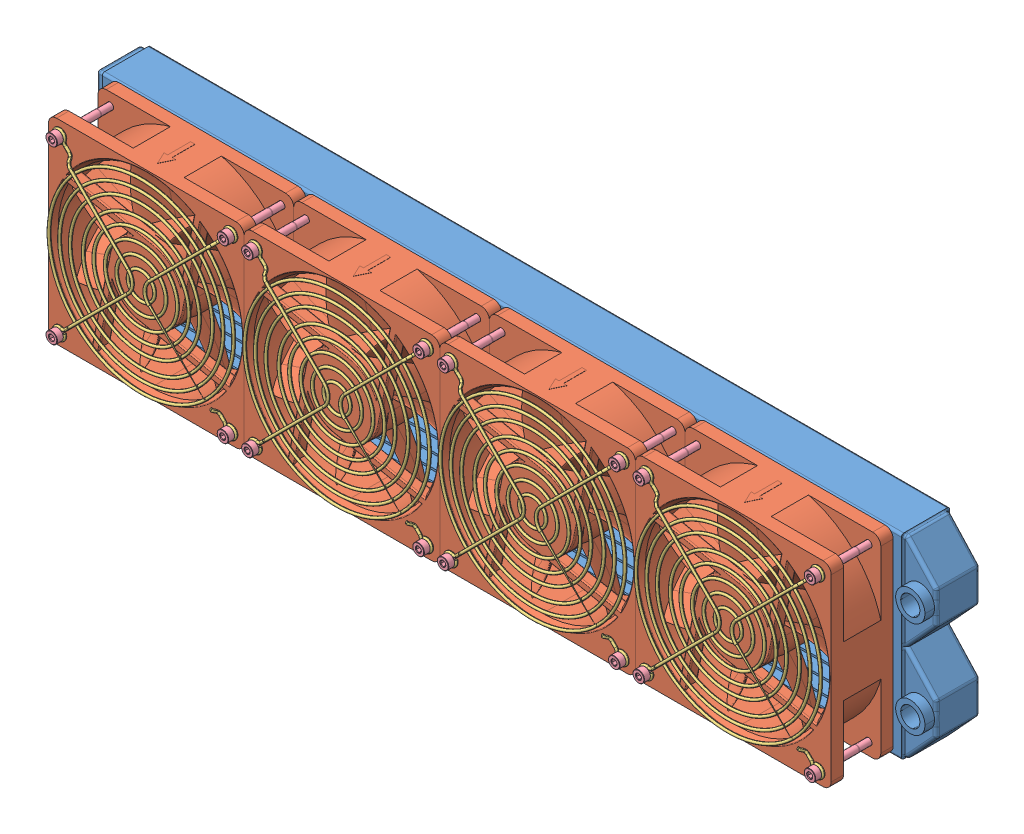
SolidWorks assembly EN-A0201-AA-4x Koolance Radiator Assembly, configuration Default. Lengths in mm.
Overall size (573.51 213.64 79.1).
25 component instances, 4 part files, 60 mates.
Components (placement in the parent):
- EN-00045-AA-CU1320V-1: EN-00045-AA-CU1320V [Default] at (-252.5 -60 -14.8) size (515 120 34.1)
- EN-00046-12038HBK-184 (Fan)-1: EN-00046-12038HBK-184 (Fan) [Default] at (121.332 -8.1772 33.6) x (-1 0 0) z (0 0 -1) size (120.02 137.53 39.89)
- EN-00046-12038HBK-184 (Fan)-2: EN-00046-12038HBK-184 (Fan) [Default] at (1.332 -8.1772 33.6) x (-1 0 0) z (0 0 -1) size (120.02 137.53 39.89)
- EN-00046-12038HBK-184 (Fan)-3: EN-00046-12038HBK-184 (Fan) [Default] at (-118.668 -8.1772 33.6) x (-1 0 0) z (0 0 -1) size (120.02 137.53 39.89)
- EN-00046-12038HBK-184 (Fan)-4: EN-00046-12038HBK-184 (Fan) [Default] at (-238.668 -8.1772 33.6) x (-1 0 0) z (0 0 -1) size (120.02 137.53 39.89)
- EN-00078-AA-GRL-AP002P (Grill)-1: EN-00078-AA-GRL-AP002P (Grill) [Default] at (172.4974 0.0026 55.8) x (-0.707107 -0.707107 0) z (-0.707107 0.707107 0) size (156.8 13.6 156.8)
- EN-00078-AA-GRL-AP002P (Grill)-3: EN-00078-AA-GRL-AP002P (Grill) [Default] at (52.4974 0.0026 55.8) x (-0.707107 -0.707107 0) z (-0.707107 0.707107 0) size (156.8 13.6 156.8)
- EN-00078-AA-GRL-AP002P (Grill)-4: EN-00078-AA-GRL-AP002P (Grill) [Default] at (-67.5026 0.0026 55.8) x (-0.707107 -0.707107 0) z (-0.707107 0.707107 0) size (156.8 13.6 156.8)
- EN-00078-AA-GRL-AP002P (Grill)-5: EN-00078-AA-GRL-AP002P (Grill) [Default] at (-187.5026 0.0026 55.8) x (-0.707107 -0.707107 0) z (-0.707107 0.707107 0) size (156.8 13.6 156.8)
- FS-BLACK-OXIDE C12.9 SHCS, M4x0.7-45 (91290A145)-17: FS-BLACK-OXIDE C12.9 SHCS, M4x0.7-45 (91290A145) [91290A145] at (-240.0052 52.5052 34) x (0.985048 0.172278 0) z (0 0 1) size (7 7 49.04)
- FS-BLACK-OXIDE C12.9 SHCS, M4x0.7-45 (91290A145)-18: FS-BLACK-OXIDE C12.9 SHCS, M4x0.7-45 (91290A145) [91290A145] at (-240.0052 -52.5 34) x (0.940441 0.339956 0) z (0 0 1) size (7 7 49.04)
- FS-BLACK-OXIDE C12.9 SHCS, M4x0.7-45 (91290A145)-19: FS-BLACK-OXIDE C12.9 SHCS, M4x0.7-45 (91290A145) [91290A145] at (-135 52.5052 34) size (7 7 49.04)
- FS-BLACK-OXIDE C12.9 SHCS, M4x0.7-45 (91290A145)-20: FS-BLACK-OXIDE C12.9 SHCS, M4x0.7-45 (91290A145) [91290A145] at (-135 -52.5 34) size (7 7 49.04)
- FS-BLACK-OXIDE C12.9 SHCS, M4x0.7-45 (91290A145)-21: FS-BLACK-OXIDE C12.9 SHCS, M4x0.7-45 (91290A145) [91290A145] at (-120.0052 -52.5 34) size (7 7 49.04)
- FS-BLACK-OXIDE C12.9 SHCS, M4x0.7-45 (91290A145)-22: FS-BLACK-OXIDE C12.9 SHCS, M4x0.7-45 (91290A145) [91290A145] at (-15 -52.5 34) size (7 7 49.04)
- FS-BLACK-OXIDE C12.9 SHCS, M4x0.7-45 (91290A145)-23: FS-BLACK-OXIDE C12.9 SHCS, M4x0.7-45 (91290A145) [91290A145] at (-15 52.5052 34) size (7 7 49.04)
- FS-BLACK-OXIDE C12.9 SHCS, M4x0.7-45 (91290A145)-24: FS-BLACK-OXIDE C12.9 SHCS, M4x0.7-45 (91290A145) [91290A145] at (-120.0052 52.5052 34) size (7 7 49.04)
- FS-BLACK-OXIDE C12.9 SHCS, M4x0.7-45 (91290A145)-25: FS-BLACK-OXIDE C12.9 SHCS, M4x0.7-45 (91290A145) [91290A145] at (-0.0052 52.5052 34) size (7 7 49.04)
- FS-BLACK-OXIDE C12.9 SHCS, M4x0.7-45 (91290A145)-26: FS-BLACK-OXIDE C12.9 SHCS, M4x0.7-45 (91290A145) [91290A145] at (105 52.5052 34) size (7 7 49.04)
- FS-BLACK-OXIDE C12.9 SHCS, M4x0.7-45 (91290A145)-27: FS-BLACK-OXIDE C12.9 SHCS, M4x0.7-45 (91290A145) [91290A145] at (105 -52.5 34) size (7 7 49.04)
- FS-BLACK-OXIDE C12.9 SHCS, M4x0.7-45 (91290A145)-28: FS-BLACK-OXIDE C12.9 SHCS, M4x0.7-45 (91290A145) [91290A145] at (-0.0052 -52.5 34) size (7 7 49.04)
- FS-BLACK-OXIDE C12.9 SHCS, M4x0.7-45 (91290A145)-29: FS-BLACK-OXIDE C12.9 SHCS, M4x0.7-45 (91290A145) [91290A145] at (119.9948 -52.5 34) size (7 7 49.04)
- FS-BLACK-OXIDE C12.9 SHCS, M4x0.7-45 (91290A145)-30: FS-BLACK-OXIDE C12.9 SHCS, M4x0.7-45 (91290A145) [91290A145] at (119.9948 52.5052 34) size (7 7 49.04)
- FS-BLACK-OXIDE C12.9 SHCS, M4x0.7-45 (91290A145)-31: FS-BLACK-OXIDE C12.9 SHCS, M4x0.7-45 (91290A145) [91290A145] at (225 52.5052 34) size (7 7 49.04)
- FS-BLACK-OXIDE C12.9 SHCS, M4x0.7-45 (91290A145)-32: FS-BLACK-OXIDE C12.9 SHCS, M4x0.7-45 (91290A145) [91290A145] at (225 -52.5 34) size (7 7 49.04)
Mates (geometry in assembly coordinates):
- Coincident1: coincident anti-aligned: plane of EN-00045-AA-CU1320V-1 through (-252.5 -60 14.8) normal (0 0 1); plane of EN-00046-12038HBK-184 (Fan)-1 through (232.5004 -60.0004 14.8) normal (0 0 -1)
- Concentric1: concentric anti-aligned: cylinder of EN-00045-AA-CU1320V-1 through (225 -52.5 14.8) axis (0 0 1) radius 1.65; cylinder of EN-00046-12038HBK-184 (Fan)-1 through (225 -52.5 52.8) axis (0 0 -1) radius 2.1001
- Parallel1: parallel aligned: plane of EN-00045-AA-CU1320V-1 through (-252.5 -60 14.8) normal (0 -1 0); plane of EN-00046-12038HBK-184 (Fan)-1 through (232.5004 -60.0004 14.8) normal (0 -1 0)
- Coincident3: coincident anti-aligned: plane of EN-00045-AA-CU1320V-1 through (-252.5 -60 14.8) normal (0 0 1); plane of EN-00046-12038HBK-184 (Fan)-2 through (112.5004 -60.0004 14.8) normal (0 0 -1)
- Concentric2: concentric anti-aligned: cylinder of EN-00045-AA-CU1320V-1 through (105 -52.5 14.8) axis (0 0 1) radius 1.65; cylinder of EN-00046-12038HBK-184 (Fan)-2 through (105 -52.5 52.8) axis (0 0 -1) radius 2.1001
- Parallel2: parallel aligned: plane of EN-00045-AA-CU1320V-1 through (-252.5 -60 14.8) normal (0 -1 0); plane of EN-00046-12038HBK-184 (Fan)-2 through (112.5004 -60.0004 14.8) normal (0 -1 0)
- Coincident5: coincident anti-aligned: plane of EN-00045-AA-CU1320V-1 through (-252.5 -60 14.8) normal (0 0 1); plane of EN-00046-12038HBK-184 (Fan)-3 through (-7.4996 -60.0004 14.8) normal (0 0 -1)
- Concentric3: concentric anti-aligned: cylinder of EN-00045-AA-CU1320V-1 through (-15 -52.5 14.8) axis (0 0 1) radius 1.65; cylinder of EN-00046-12038HBK-184 (Fan)-3 through (-15 -52.5 52.8) axis (0 0 -1) radius 2.1001
- Parallel3: parallel aligned: plane of EN-00045-AA-CU1320V-1 through (-252.5 -60 14.8) normal (0 -1 0); plane of EN-00046-12038HBK-184 (Fan)-3 through (-7.4996 -60.0004 14.8) normal (0 -1 0)
- Coincident7: coincident anti-aligned: plane of EN-00045-AA-CU1320V-1 through (-252.5 -60 14.8) normal (0 0 1); plane of EN-00046-12038HBK-184 (Fan)-4 through (-127.4996 -60.0004 14.8) normal (0 0 -1)
- Concentric4: concentric anti-aligned: cylinder of EN-00045-AA-CU1320V-1 through (-135 -52.5 14.8) axis (0 0 1) radius 1.65; cylinder of EN-00046-12038HBK-184 (Fan)-4 through (-135 -52.5 52.8) axis (0 0 -1) radius 2.1001
- Parallel4: parallel aligned: plane of EN-00045-AA-CU1320V-1 through (-252.5 -60 14.8) normal (0 -1 0); plane of EN-00046-12038HBK-184 (Fan)-4 through (-127.4996 -60.0004 14.8) normal (0 -1 0)
- Distance1: distance = 60 mm: plane of assembly through (0 0 0) normal (0 1 0); plane of assembly; plane of EN-00045-AA-CU1320V-1 through (-252.5 -60 14.8) normal (0 -1 0)
- Distance2: distance = 257.5 mm: plane of assembly through (0 0 0) normal (1 0 0); plane of assembly; plane of EN-00045-AA-CU1320V-1 through (-257.5 -60 -14.8) normal (-1 0 0)
- Distance3: distance = 14.8 mm: plane of assembly through (0 0 0) normal (0 0 1); plane of assembly; plane of EN-00045-AA-CU1320V-1 through (-252.5 -60 -14.8) normal (0 0 -1)
- Coincident8: coincident aligned: plane of EN-00046-12038HBK-184 (Fan)-1 through (232.5004 -60.0004 52.8) normal (0 0 1); plane of EN-00078-AA-GRL-AP002P (Grill)-1 through (172.4974 0.0026 52.8) normal (0 0 1)
- Concentric5: concentric aligned: cylinder of EN-00046-12038HBK-184 (Fan)-1 through (172.4974 0.0026 47.6487) axis (0 0 -1) radius 23.2442; circle of EN-00078-AA-GRL-AP002P (Grill)-1
- Distance4: distance = 0.0504 mm: point of EN-00078-AA-GRL-AP002P (Grill)-1
- Coincident13: coincident aligned: plane of EN-00046-12038HBK-184 (Fan)-2 through (112.5004 -60.0004 52.8) normal (0 0 1); plane of EN-00078-AA-GRL-AP002P (Grill)-2 through (14655.4509 -24504.2017 52.8) normal (0 0 1)
- Coincident14: coincident aligned: plane of EN-00046-12038HBK-184 (Fan)-2 through (112.5004 -60.0004 52.8) normal (0 0 1); plane of EN-00078-AA-GRL-AP002P (Grill)-3 through (52.4974 0.0026 52.8) normal (0 0 1)
- Concentric6: concentric aligned: cylinder of EN-00046-12038HBK-184 (Fan)-2 through (52.4974 0.0026 47.6487) axis (0 0 -1) radius 23.2442; circle of EN-00078-AA-GRL-AP002P (Grill)-3
- Distance5: distance = 0.0504 mm: unknown of EN-00078-AA-GRL-AP002P (Grill)-3
- Coincident16: coincident aligned: plane of EN-00046-12038HBK-184 (Fan)-3 through (-7.4996 -60.0004 52.8) normal (0 0 1); plane of EN-00078-AA-GRL-AP002P (Grill)-4 through (-67.5026 0.0026 52.8) normal (0 0 1)
- Concentric7: concentric aligned: cylinder of EN-00046-12038HBK-184 (Fan)-3 through (-67.5026 0.0026 47.6487) axis (0 0 -1) radius 23.2442; circle of EN-00078-AA-GRL-AP002P (Grill)-4
- Distance7: distance = 0.0504 mm: unknown of EN-00078-AA-GRL-AP002P (Grill)-4
- Coincident20: coincident aligned: plane of EN-00046-12038HBK-184 (Fan)-4 through (-127.4996 -60.0004 52.8) normal (0 0 1); plane of EN-00078-AA-GRL-AP002P (Grill)-5 through (-187.5026 0.0026 52.8) normal (0 0 1)
- Concentric8: concentric aligned: cylinder of EN-00046-12038HBK-184 (Fan)-4 through (-187.5026 0.0026 47.6487) axis (0 0 -1) radius 23.2442; circle of EN-00078-AA-GRL-AP002P (Grill)-5
- Distance8: distance = 0.0504 mm: unknown of EN-00078-AA-GRL-AP002P (Grill)-5
- Concentric9: concentric aligned: cylinder of EN-00046-12038HBK-184 (Fan)-4 through (-240.0052 52.5052 52.8) axis (0 0 -1) radius 2.1001; cylinder of FS-BLACK-OXIDE C12.9 SHCS, M4x0.7-45 (91290A145)-1 through (-240.0052 52.5052 9.5) axis (0 0 -1) radius 2.0758
- Tangent1: tangent: plane of assembly; face of EN-00078-AA-GRL-AP002P (Grill)-5; plane of FS-BLACK-OXIDE C12.9 SHCS, M4x0.7-45 (91290A145)-17 through (-240.5738 55.7559 54.5) normal (0 0 -1)
- Concentric10: concentric aligned: cylinder of EN-00046-12038HBK-184 (Fan)-4 through (-240.0052 -52.5 52.8) axis (0 0 -1) radius 2.1001; cylinder of FS-BLACK-OXIDE C12.9 SHCS, M4x0.7-45 (91290A145)-2 through (-240.0052 -52.5 9.5) axis (0 0 -1) radius 2.0758
- Tangent2: tangent: plane of assembly; face of EN-00078-AA-GRL-AP002P (Grill)-5; plane of FS-BLACK-OXIDE C12.9 SHCS, M4x0.7-45 (91290A145)-18 through (-241.1271 -49.3965 54.5) normal (0 0 -1)
- Concentric11: concentric aligned: cylinder of EN-00046-12038HBK-184 (Fan)-4 through (-135 52.5052 52.8) axis (0 0 -1) radius 2.1001; cylinder of FS-BLACK-OXIDE C12.9 SHCS, M4x0.7-45 (91290A145)-3 through (-135 52.5052 9.5) axis (0 0 -1) radius 2.0758
- Tangent3: tangent: plane of assembly; face of EN-00078-AA-GRL-AP002P (Grill)-5; plane of FS-BLACK-OXIDE C12.9 SHCS, M4x0.7-45 (91290A145)-19 through (-135 55.8052 54.5) normal (0 0 -1)
- Concentric12: concentric aligned: cylinder of EN-00046-12038HBK-184 (Fan)-4 through (-135 -52.5 52.8) axis (0 0 -1) radius 2.1001; cylinder of FS-BLACK-OXIDE C12.9 SHCS, M4x0.7-45 (91290A145)-4 through (-135 -52.5 9.5) axis (0 0 -1) radius 2.0758
- Tangent4: tangent: plane of assembly; face of EN-00078-AA-GRL-AP002P (Grill)-5; plane of FS-BLACK-OXIDE C12.9 SHCS, M4x0.7-45 (91290A145)-20 through (-135 -49.2 54.5) normal (0 0 -1)
- Concentric13: concentric aligned: cylinder of EN-00046-12038HBK-184 (Fan)-3 through (-120.0052 -52.5 52.8) axis (0 0 -1) radius 2.1001; cylinder of FS-BLACK-OXIDE C12.9 SHCS, M4x0.7-45 (91290A145)-5 through (-120.0052 -52.5 9.5) axis (0 0 -1) radius 2.0758
- Tangent5: tangent: plane of assembly; face of EN-00078-AA-GRL-AP002P (Grill)-4; plane of FS-BLACK-OXIDE C12.9 SHCS, M4x0.7-45 (91290A145)-21 through (-120.0052 -49.2 54.5) normal (0 0 -1)
- Concentric14: concentric aligned: cylinder of EN-00046-12038HBK-184 (Fan)-3 through (-15 -52.5 52.8) axis (0 0 -1) radius 2.1001; cylinder of FS-BLACK-OXIDE C12.9 SHCS, M4x0.7-45 (91290A145)-6 through (-15 -52.5 9.5) axis (0 0 -1) radius 2.0758
- Tangent6: tangent: plane of assembly; face of EN-00078-AA-GRL-AP002P (Grill)-4; plane of FS-BLACK-OXIDE C12.9 SHCS, M4x0.7-45 (91290A145)-22 through (-15 -49.2 54.5) normal (0 0 -1)
- Concentric15: concentric aligned: cylinder of EN-00046-12038HBK-184 (Fan)-3 through (-15 52.5052 52.8) axis (0 0 -1) radius 2.1001; cylinder of FS-BLACK-OXIDE C12.9 SHCS, M4x0.7-45 (91290A145)-7 through (-15 52.5052 9.5) axis (0 0 -1) radius 2.0758
- Tangent7: tangent: plane of assembly; face of EN-00078-AA-GRL-AP002P (Grill)-4; plane of FS-BLACK-OXIDE C12.9 SHCS, M4x0.7-45 (91290A145)-23 through (-15 55.8052 54.5) normal (0 0 -1)
- Concentric16: concentric aligned: cylinder of EN-00046-12038HBK-184 (Fan)-3 through (-120.0052 52.5052 52.8) axis (0 0 -1) radius 2.1001; cylinder of FS-BLACK-OXIDE C12.9 SHCS, M4x0.7-45 (91290A145)-8 through (-120.0052 52.5052 9.5) axis (0 0 -1) radius 2.0758
- Tangent8: tangent: plane of assembly; face of EN-00078-AA-GRL-AP002P (Grill)-4; plane of FS-BLACK-OXIDE C12.9 SHCS, M4x0.7-45 (91290A145)-24 through (-120.0052 55.8052 54.5) normal (0 0 -1)
- Concentric17: concentric aligned: cylinder of EN-00046-12038HBK-184 (Fan)-2 through (-0.0052 52.5052 52.8) axis (0 0 -1) radius 2.1001; cylinder of FS-BLACK-OXIDE C12.9 SHCS, M4x0.7-45 (91290A145)-9 through (-0.0052 52.5052 9.5) axis (0 0 -1) radius 2.0758
- Tangent9: tangent: plane of assembly; face of EN-00078-AA-GRL-AP002P (Grill)-3; plane of FS-BLACK-OXIDE C12.9 SHCS, M4x0.7-45 (91290A145)-25 through (-0.0052 55.8052 54.5) normal (0 0 -1)
- Concentric18: concentric aligned: cylinder of EN-00046-12038HBK-184 (Fan)-2 through (105 52.5052 52.8) axis (0 0 -1) radius 2.1001; cylinder of FS-BLACK-OXIDE C12.9 SHCS, M4x0.7-45 (91290A145)-10 through (105 52.5052 9.5) axis (0 0 -1) radius 2.0758
- Tangent10: tangent: plane of assembly; face of EN-00078-AA-GRL-AP002P (Grill)-3; plane of FS-BLACK-OXIDE C12.9 SHCS, M4x0.7-45 (91290A145)-26 through (105 55.8052 54.5) normal (0 0 -1)
- Concentric19: concentric aligned: cylinder of EN-00046-12038HBK-184 (Fan)-2 through (105 -52.5 52.8) axis (0 0 -1) radius 2.1001; cylinder of FS-BLACK-OXIDE C12.9 SHCS, M4x0.7-45 (91290A145)-11 through (105 -52.5 9.5) axis (0 0 -1) radius 2.0758
- Tangent11: tangent: plane of assembly; face of EN-00078-AA-GRL-AP002P (Grill)-3; plane of FS-BLACK-OXIDE C12.9 SHCS, M4x0.7-45 (91290A145)-27 through (105 -49.2 54.5) normal (0 0 -1)
- Concentric20: concentric aligned: cylinder of EN-00046-12038HBK-184 (Fan)-2 through (-0.0052 -52.5 52.8) axis (0 0 -1) radius 2.1001; cylinder of FS-BLACK-OXIDE C12.9 SHCS, M4x0.7-45 (91290A145)-12 through (-0.0052 -52.5 9.5) axis (0 0 -1) radius 2.0758
- Tangent12: tangent: plane of assembly; face of EN-00078-AA-GRL-AP002P (Grill)-3; plane of FS-BLACK-OXIDE C12.9 SHCS, M4x0.7-45 (91290A145)-28 through (-0.0052 -49.2 54.5) normal (0 0 -1)
- Concentric21: concentric aligned: cylinder of EN-00046-12038HBK-184 (Fan)-1 through (119.9948 -52.5 52.8) axis (0 0 -1) radius 2.1001; cylinder of FS-BLACK-OXIDE C12.9 SHCS, M4x0.7-45 (91290A145)-13 through (119.9948 -52.5 9.5) axis (0 0 -1) radius 2.0758
- Tangent13: tangent: plane of assembly; face of EN-00078-AA-GRL-AP002P (Grill)-1; plane of FS-BLACK-OXIDE C12.9 SHCS, M4x0.7-45 (91290A145)-29 through (119.9948 -49.2 54.5) normal (0 0 -1)
- Concentric22: concentric aligned: cylinder of EN-00046-12038HBK-184 (Fan)-1 through (119.9948 52.5052 52.8) axis (0 0 -1) radius 2.1001; cylinder of FS-BLACK-OXIDE C12.9 SHCS, M4x0.7-45 (91290A145)-14 through (119.9948 52.5052 9.5) axis (0 0 -1) radius 2.0758
- Tangent14: tangent: plane of assembly; face of EN-00078-AA-GRL-AP002P (Grill)-1; plane of FS-BLACK-OXIDE C12.9 SHCS, M4x0.7-45 (91290A145)-30 through (119.9948 55.8052 54.5) normal (0 0 -1)
- Concentric23: concentric aligned: cylinder of EN-00046-12038HBK-184 (Fan)-1 through (225 52.5052 52.8) axis (0 0 -1) radius 2.1001; cylinder of FS-BLACK-OXIDE C12.9 SHCS, M4x0.7-45 (91290A145)-15 through (225 52.5052 9.5) axis (0 0 -1) radius 2.0758
- Tangent15: tangent: plane of assembly; face of EN-00078-AA-GRL-AP002P (Grill)-1; plane of FS-BLACK-OXIDE C12.9 SHCS, M4x0.7-45 (91290A145)-31 through (225 55.8052 54.5) normal (0 0 -1)
- Concentric24: concentric aligned: cylinder of EN-00046-12038HBK-184 (Fan)-1 through (225 -52.5 52.8) axis (0 0 -1) radius 2.1001; cylinder of FS-BLACK-OXIDE C12.9 SHCS, M4x0.7-45 (91290A145)-16 through (225 -52.5 9.5) axis (0 0 -1) radius 2.0758
- Tangent16: tangent: plane of assembly; face of EN-00078-AA-GRL-AP002P (Grill)-1; plane of FS-BLACK-OXIDE C12.9 SHCS, M4x0.7-45 (91290A145)-32 through (225 -49.2 54.5) normal (0 0 -1)
